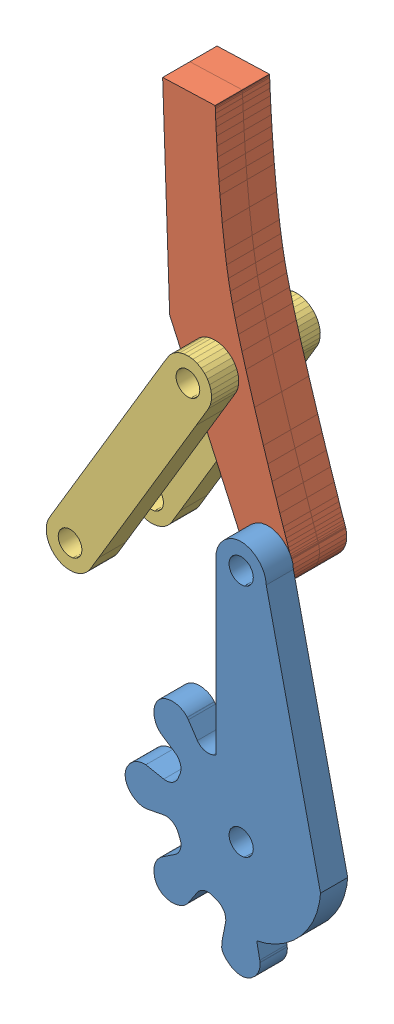
SolidWorks assembly Assem7, configuration Default. Lengths in mm.
Overall size (37.06 92.34 14).
5 component instances, 3 part files, 4 mates.
Components (placement in the parent):
- gripper4-1: gripper4 [Default] at origin size (25.94 48.83 3.5)
- gripper3-1: gripper3 [Default] at (1.7803 39.5897 -3.5) x (0.999394 0.034796 0) z (0 0 1) size (15.08 50 3.5)
- gripper1-1: gripper1 [Default] at (-6.0302 33.0602 0) x (0.512731 0.858549 0) z (0 0 1) size (35.69 6.12 3.5)
- gripper3-2: gripper3 [Default] at (1.7803 39.5897 -7) x (0.999394 0.034796 0) z (0 0 1) size (15.08 50 3.5)
- gripper1-2: gripper1 [Default] at (-6.0302 33.0602 -10.5) x (0.512731 0.858549 0) z (0 0 1) size (35.69 6.12 3.5)
Mates (geometry in assembly coordinates):
- Coincident1: coincident anti-aligned: plane of gripper4-1 through (13.0408 21.4113 0) normal (0 0 -1); plane of gripper3-1 through (8.3707 67.3417 0) normal (0 0 1)
- Concentric1: concentric aligned: cylinder of gripper4-1 through (14.9476 45.1852 0) axis (0 0 1) radius 1.563; cylinder of gripper3-1 through (14.9476 45.1852 -3.5) axis (0 0 1) radius 1.563
- Coincident2: coincident anti-aligned: plane of gripper3-1 through (8.3707 67.3417 0) normal (0 0 1); plane of gripper1-1 through (0.4943 49.953 0) normal (0 0 -1)
- Concentric3: concentric aligned: cylinder of gripper3-1 through (8.0869 62.6534 -3.5) axis (0 0 1) radius 1.5595; cylinder of gripper1-1 through (8.0869 62.6534 0) axis (0 0 1) radius 1.53
